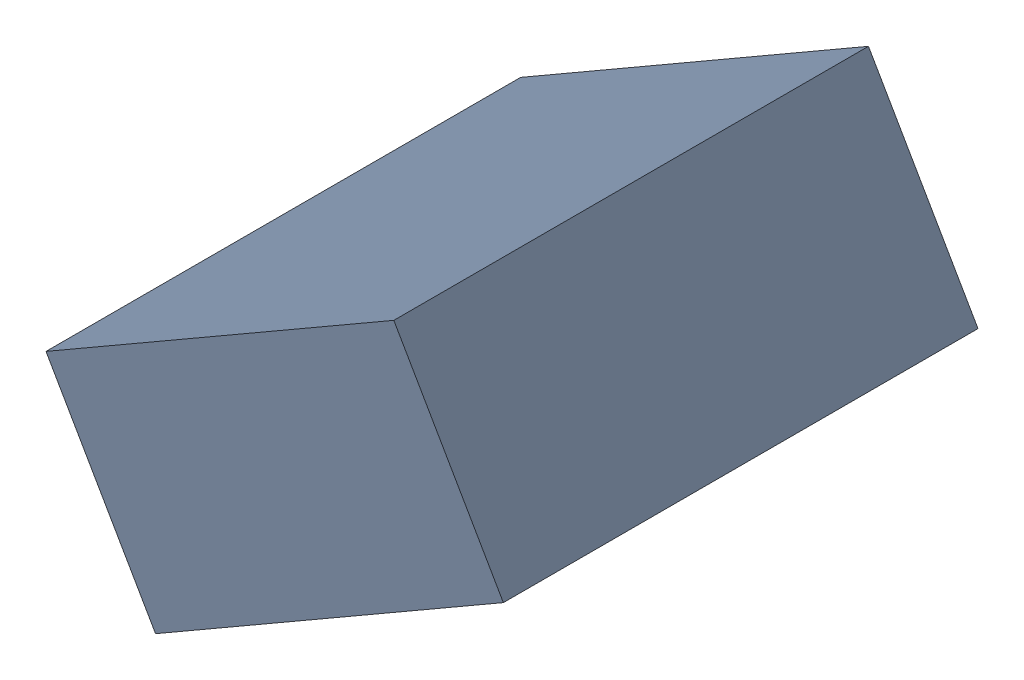
SolidWorks assembly C31_TDA5, configuration Standard. Lengths in mm.
Overall size (1.25 1.07 1.3).
2 component instances, 1 part files, 0 mates.
Components (placement in the parent):
- 885542920-1: 885542920 [Standard] at (-50.7512 -33.3123 0) size (1.25 1.07 1.3)
  - Extruded_24-1: Extruded_24 [Standard] at origin size (1.25 1.07 1.3)
